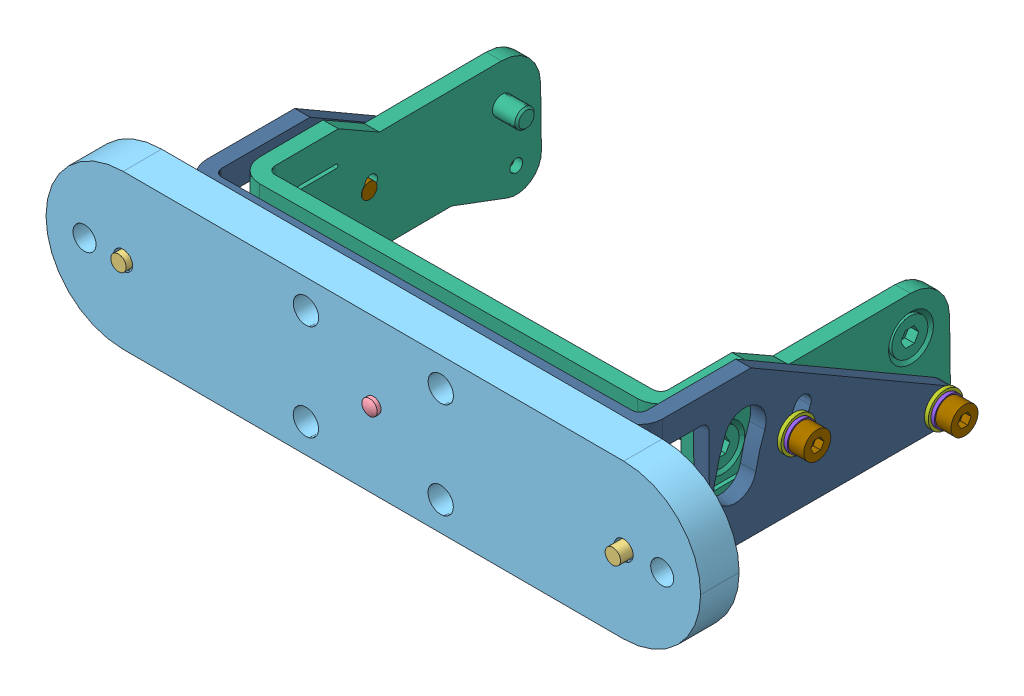
SolidWorks assembly LMBrace, configuration Default. Lengths in mm.
Overall size (150.05 42.84 97.61).
25 component instances, 10 part files, 5 mates.
Components (placement in the parent):
- LMBrace_P3-1: LMBrace_P3 [Default] at (56.5692 113.5614 102.526) size (150.05 40.17 15.65)
  - Scheibe_DIN_125_4.3_PA_5.1-1: Scheibe_DIN_125_4.3_PA_5.1 [Default] at (83.8747 -70.3905 67.8831) x (-1 0 -0.00017) z (0.00017 0 -1) size (9 9 1)
  - Federring_DIN_127_-_B_4.1_5.1-1: Federring_DIN_127_-_B_4.1_5.1 [Default] at (68.0288 -31.3454 66.8804) x (0.00017 0 -1) z (1 0 0.00017) size (0.9 7.6 7.45)
  - Scheibe_DIN_125_4.3_PA_5.1-2: Scheibe_DIN_125_4.3_PA_5.1 [Default] at (-46.1249 -70.2456 66.232) x (-1 0 -0.00017) z (0.00017 0 -1) size (9 9 1)
  - Federring_DIN_127_-_B_4.1_5.1-2: Federring_DIN_127_-_B_4.1_5.1 [Default] at (-61.9708 -31.2005 65.2293) x (0.00017 0 -1) z (1 0 0.00017) size (0.9 7.6 7.45)
  - Zylinderschraube_DIN_912_M4x10-A2_5.1-1: Zylinderschraube_DIN_912_M4x10-A2_5.1 [Default] at (68.0104 -62.8454 175.5876) x (0 1 0) z (-1 0 -0.00017) size (7 14 7)
  - Zylinderschraube_DIN_912_M4x10-A2_5.1-2: Zylinderschraube_DIN_912_M4x10-A2_5.1 [Default] at (-61.9893 -62.7005 173.9365) x (0 1 0) z (-1 0 -0.00017) size (7 14 7)
  - Zylinderstift_DIN_7-4_m6_x_8.1-1: Zylinderstift_DIN_7-4_m6_x_8.1 [Default] at (3.029 -31.273 66.1405) x (-0.00017 0 1) z (1 0 0.00017) size (9.2 4.07 4.31)
  - SickLMS_Suport_P1-1: SickLMS_Suport_P1 [Default] at (3.0278 -31.273 73.1613) x (-0.999999 0.001114 -0.00017) z (0.00017 0 -1) size (150 40 10)
- LMBrace_P1-1: LMBrace_P1 [Default] at (59.1769 118.5702 96.2544) x (0.999969 0.007815 0) z (0.000046 -0.005938 0.999982) size (110.21 37.92 74.76)
  - 2034324-1: 2034324 [Default] at (-55.1095 -20.3374 55.7306) x (1 0 0.00017) z (0.00017 0 -1) size (110.2 37.92 74.74)
- LMBrace_P2-1: LMBrace_P2 [Default] at (142.2509 104.4346 121.7058) x (0.999969 0.007814 0) z (0 0.000001 1) size (139.39 39.28 84.12)
  - Scheibe_DIN_125_4.3_PA_4.1-1: Scheibe_DIN_125_4.3_PA_4.1 [Default] at (-142.0523 -36.66 -76.3859) x (-0.000065 0.924426 0.381362) z (1 0 0.00017) size (9 9 1)
  - Federring_DIN_127_-_B_4.1_2.1-1: Federring_DIN_127_-_B_4.1_2.1 [Default] at (-141.0595 -36.9018 -34.2484) x (1 0 0.00017) z (0.000065 -0.924426 -0.381362) size (0.9 7.6 7.45)
  - Zylinderschraube_DIN_912_M4x10-A2_1.1-1: Zylinderschraube_DIN_912_M4x10-A2_1.1 [Default] at (-249.7716 -48.9147 -5.1474) x (0.000157 0.381362 -0.924426) z (0.000065 -0.924426 -0.381362) size (7 14 7)
  - Scheibe_DIN_125_4.3_PA_4.1-2: Scheibe_DIN_125_4.3_PA_4.1 [Default] at (-142.0633 -62.5317 -11.9897) x (-0.00017 0 1) z (-1 0 -0.00017) size (9 9 1)
  - Federring_DIN_127_-_B_4.1_2.1-2: Federring_DIN_127_-_B_4.1_2.1 [Default] at (-143.0659 -23.4866 3.8563) x (-1 0 -0.00017) z (0.00017 0 -1) size (0.9 7.6 7.45)
  - Zylinderschraube_DIN_912_M4x10-A2_1.1-2: Zylinderschraube_DIN_912_M4x10-A2_1.1 [Default] at (-34.3588 -54.9866 3.8747) x (0 1 0) z (-0.00017 0 1) size (7 14 7)
  - Federring_DIN_127_-_B_4.1_2.1-3: Federring_DIN_127_-_B_4.1_2.1 [Default] at (-21.6595 -36.9018 -34.2281) x (-1 0 -0.00017) z (0.00017 0 -1) size (0.9 7.6 7.45)
  - Scheibe_DIN_125_4.3_PA_4.1-3: Scheibe_DIN_125_4.3_PA_4.1 [Default] at (-23.5568 2.1433 -50.0745) x (-0.00017 0 1) z (1 0 0.00017) size (9 9 1)
  - Scheibe_DIN_125_4.3_PA_4.1-4: Scheibe_DIN_125_4.3_PA_4.1 [Default] at (-22.5633 -62.5317 -11.9694) x (-0.00017 0 1) z (-1 0 -0.00017) size (9 9 1)
  - Federring_DIN_127_-_B_4.1_2.1-4: Federring_DIN_127_-_B_4.1_2.1 [Default] at (-21.6659 -23.4866 3.8769) x (-1 0 -0.00017) z (0.00017 0 -1) size (0.9 7.6 7.45)
  - Zylinderschraube_DIN_912_M4x10-A2_1.1-3: Zylinderschraube_DIN_912_M4x10-A2_1.1 [Default] at (-131.2667 -68.4018 -34.2467) x (0 1 0) z (0.00017 0 -1) size (7 14 7)
  - Zylinderschraube_DIN_912_M4x10-A2_1.1-4: Zylinderschraube_DIN_912_M4x10-A2_1.1 [Default] at (-131.2731 -54.9866 3.8583) x (0 1 0) z (0.00017 0 -1) size (7 14 7)
  - 4043069_Einstellbuegel.1-2: 4043069_Einstellbuegel.1 [Default] at (-138.0721 -5.4997 39.9721) x (1 0 0.00017) z (0.00017 0 -1) size (139.38 37.7 82.52)
Mates (geometry in assembly coordinates):
- Concentric1: concentric aligned: cylinder of LMBrace_P3-1/Zylinderstift_DIN_7-4_m6_x_8.1-1 through (59.5975 82.2885 172.6665) axis (-0.00017 0 1) radius 2; cylinder of LMBrace_P2-1/4043069_Einstellbuegel.1-2 through (59.6141 82.2885 74.9113) axis (-0.00017 0 1) radius 2
- Coincident1: coincident anti-aligned: plane of LMBrace_P3-1/SickLMS_Suport_P1-1 through (59.5987 82.2885 165.6873) normal (0.00017 0 -1); plane of LMBrace_P2-1/4043069_Einstellbuegel.1-2 through (104.9301 72.0424 165.695) normal (-0.00017 0 1)
- Coincident2: coincident anti-aligned: plane of LMBrace_P1-1/2034324-1 through (4.231 97.4861 149.5182) normal (-0.999969 -0.007814 -0.00017); plane of LMBrace_P2-1/4043069_Einstellbuegel.1-2 through (4.5407 58.5851 115.678) normal (0.999969 0.007814 0.00017)
- Concentric7: concentric aligned: cylinder of LMBrace_P1-1/2034324-1 through (114.6806 67.3163 87.4767) axis (0.999969 0.007814 0.00017) radius 1.65; cylinder of LMBrace_P2-1/Zylinderschraube_DIN_912_M4x10-A2_1.1-3 through (120.8804 67.3647 87.4777) axis (0.999969 0.007814 0.00017) radius 3.5
- Concentric8: concentric anti-aligned: cylinder of LMBrace_P1-1/2034324-1 through (4.484 66.4551 87.458) axis (-0.999969 -0.007814 -0.00017) radius 1.65; cylinder of LMBrace_P2-1/Zylinderschraube_DIN_912_M4x10-A2_1.1-1 through (2.3841 66.4387 87.4576) axis (0.999969 0.007814 0.00017) radius 3.5
